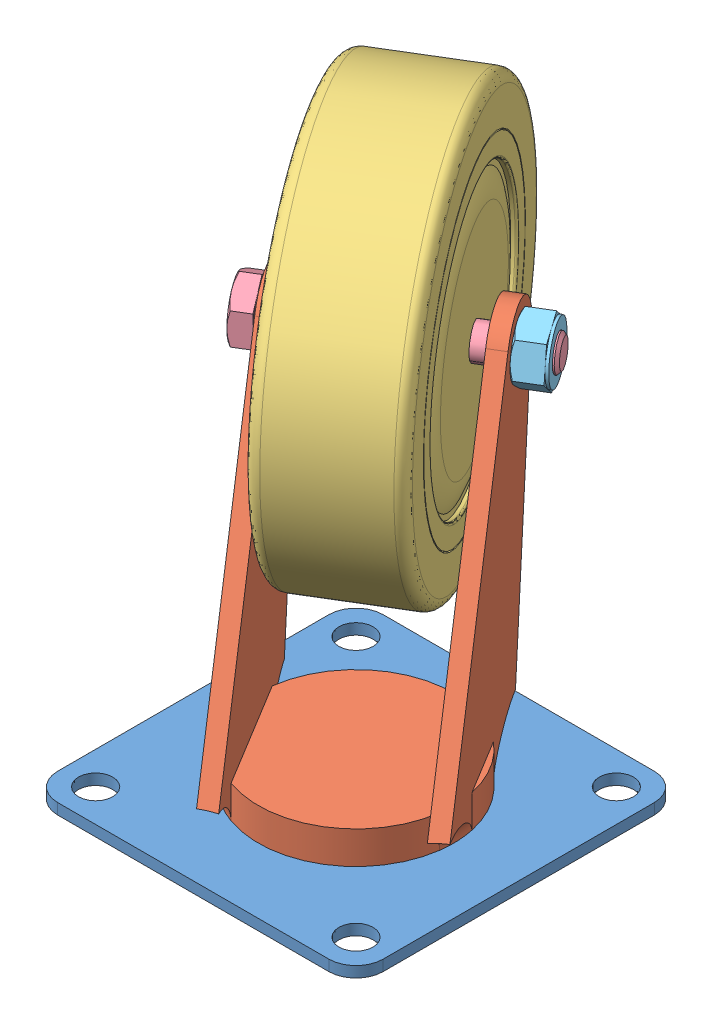
SolidWorks assembly caster_assembly, configuration Défaut. Lengths in mm.
Overall size (74.77 109.48 93.94).
5 component instances, 5 part files, 8 mates.
Components (placement in the parent):
- caster_mount-1: caster_mount [Défaut] at (0.4547 1.4301 60) size (60 5 60)
- caster_fork-1: caster_fork [Défaut] at (0.4547 6.4301 60) x (0.85474 0 -0.519057) z (-0.519057 0 -0.85474) size (36 67.25 45.68)
- caster_wheel-1: caster_wheel [Défaut] at (-9.9264 62.7801 42.9052) x (0.85474 0 -0.519057) z (0.227309 0.899011 0.374313) size (22 72 72)
- hex bolt gradeab_iso-1: hex bolt gradeab_iso [ISO 4014 - M6 x 40 x 18-N] at (-27.8759 62.7801 53.8054) x (0.85474 0 -0.519057) z (0.519057 0 0.85474) size (44 11.55 10)
- hex nut style 1 gradeab_iso-1: hex nut style 1 gradeab_iso [ISO - 4032 - M6 - W - N] at (4.6042 62.7801 34.0812) x (0.503612 0.242128 0.829306) z (-0.85474 0 0.519057) size (10 11.55 5.2)
Mates (geometry in assembly coordinates):
- Coaxiale1: concentric anti-aligned: cylinder of mount-1 through (0.4547 6.4301 60) axis (0 -1 0) radius 15; cylinder of wheelFork-1 through (0.4547 3.4301 60) axis (0 1 0) radius 15
- Coïncidente1: coincident anti-aligned: plane of mount-1 through (25.4547 3.4301 35) normal (0 1 0); plane of wheelFork-1 through (0.4547 3.4301 60) normal (0 -1 0)
- Coaxiale2: concentric aligned: cylinder of wheelFork-1 through (4.6042 62.7801 34.0812) axis (-0.85474 0 0.519057) radius 2; cylinder of caster_wheel-1 through (-0.5243 62.7801 37.1956) axis (-0.85474 0 0.519057) radius 2.5
- Coïncidente2: coincident aligned: plane of caster_fork-1 through (0.4547 6.4301 60) normal (0.85474 0 -0.519057); plane of caster_wheel-1 through (-9.9264 62.7801 42.9052) normal (0.85474 0 -0.519057)
- Concentric1: concentric anti-aligned: cylinder of caster_fork-1 through (-24.457 62.7801 51.7292) axis (0.85474 0 -0.519057) radius 2; cylinder of hex bolt gradeab_iso-1 through (-27.8759 62.7801 53.8054) axis (-0.85474 0 0.519057) radius 5
- Coincident1: coincident anti-aligned: plane of caster_fork-1 through (-24.457 62.7801 51.7292) normal (-0.85474 0 0.519057); plane of hex bolt gradeab_iso-1 through (-24.457 68.5536 51.7292) normal (0.85474 0 -0.519057)
- Concentric2: concentric aligned: cylinder of hex bolt gradeab_iso-1 through (-27.8759 62.7801 53.8054) axis (-0.85474 0 0.519057) radius 3; cylinder of hex nut style 1 gradeab_iso-1 through (26.0047 62.7801 21.0853) axis (-0.85474 0 0.519057) radius 3
- Coincident2: coincident anti-aligned: plane of caster_fork-1 through (4.6042 62.7801 34.0812) normal (0.85474 0 -0.519057); plane of hex nut style 1 gradeab_iso-1 through (3.8786 68.3818 32.8864) normal (-0.85474 0 0.519057)
